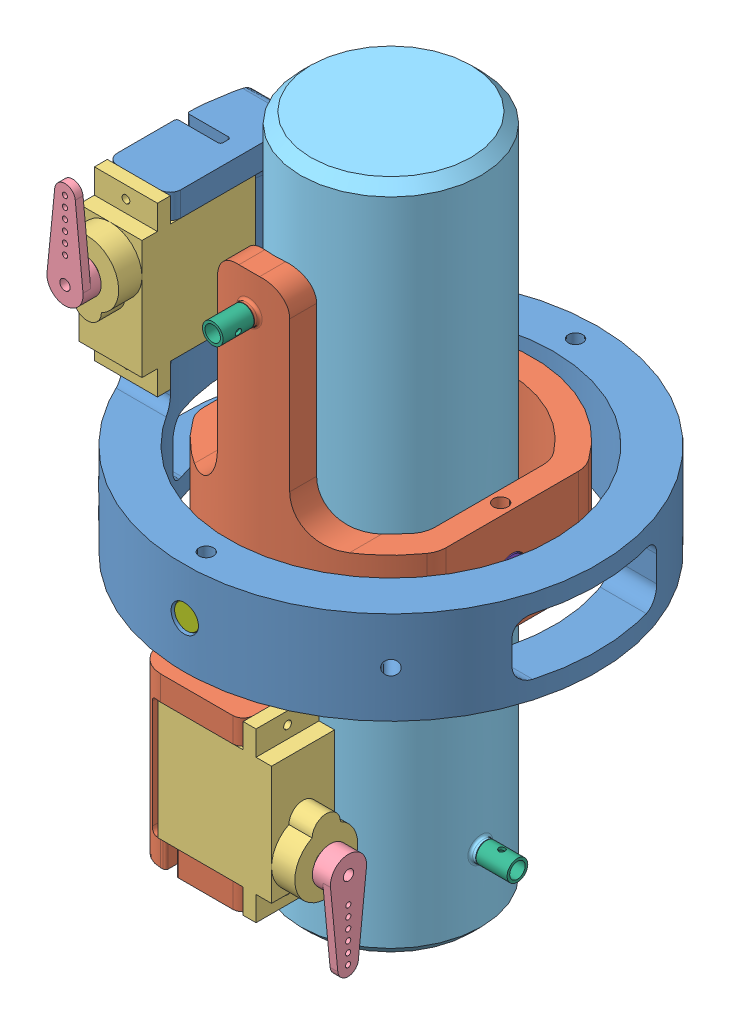
SolidWorks assembly Assemblage TVC, configuration Défaut. Lengths in mm.
Overall size (80 130 80).
13 component instances, 8 part files, 27 mates.
Components (placement in the parent):
- Cardan roulis-1: Cardan roulis [Défaut] at origin size (80 53.5 80)
- Cardan tangage-1: Cardan tangage [Défaut] at origin size (47 100.5 63.11)
- SG90-1: SG90 [Défaut] at (-33.7993 28.25 9.5) size (12.2 32.5 29.3)
- Biellette-1: Biellette [Défaut] at (-33.7993 33.65 29.3) x (-1 0 0) z (0 0 -1) size (7 20.5 3.5)
- Support moteur-1: Support moteur [Défaut] at origin size (36 130 35)
- SG90-2: SG90 [Défaut] at (1.5 -32.25 29.5139) x (0 0 1) z (1 0 0) size (12.2 32.5 29.3)
- Biellette-2: Biellette [Défaut] at (21.3 -37.65 29.5139) x (0 -0.004896 -0.999988) z (-1 0 0) size (7 20.5 3.5)
- Pivot-1: Pivot [Défaut] at (0 45 29) x (0.164225 0.986423 0) z (0 0 -1) size (4 4 11)
- Pivot-2: Pivot [Défaut] at (19 -50 0) x (0 0.007842 0.999969) z (-1 0 0) size (4 4 11)
- Axe roulis-1: Axe roulis [Défaut] at (0 0 32) size (5 5 15)
- Axe tangage-1: Axe tangage [Défaut] at (18.5 0 0) x (0 0.148183 0.98896) z (1 0 0) size (5 5 10)
- Axe roulis-2: Axe roulis [Défaut] at (0 0 -32) size (5 5 15)
- Axe tangage-2: Axe tangage [Défaut] at (-18.5 0 0) x (0 0.148183 0.98896) z (1 0 0) size (5 5 10)
Mates (geometry in assembly coordinates):
- Coïncidente1: coincident aligned: plane of Cardan roulis-1 through (0 0 0) normal (0 0 1); plane of assembly through (0 0 0) normal (0 0 1)
- Coïncidente2: coincident aligned: plane of Cardan roulis-1 through (0 0 0) normal (0 1 0); plane of assembly through (0 0 0) normal (0 1 0)
- Coïncidente3: coincident aligned: plane of Cardan roulis-1 through (0 0 0) normal (1 0 0); plane of assembly through (0 0 0) normal (1 0 0)
- Coïncidente4: coincident aligned: plane of Cardan roulis-1 through (0 0 0) normal (0 0 1); plane of Cardan tangage-1 through (0 0 0) normal (0 0 1)
- Coaxiale1: concentric aligned: cylinder of Cardan roulis-1 through (0 0 -40.001) axis (0 0 1) radius 2.65; cylinder of Cardan tangage-1 through (0 0 24.5) axis (0 0 1) radius 2.5
- Coïncidente6: coincident anti-aligned: plane of SG90-1 through (-33.7993 33.65 27.8) normal (0 0 1); plane of Biellette-1 through (-33.7993 33.65 27.8) normal (0 0 -1)
- Coaxiale2: concentric aligned: cylinder of SG90-1 through (-33.7993 33.65 27.8) axis (0 0 -1) radius 2.45; cylinder of Biellette-1 through (-33.7993 33.65 27.8) axis (0 0 -1) radius 2.45
- Coïncidente8: coincident aligned: plane of Cardan tangage-1 through (0 0 0) normal (1 0 0); plane of Support moteur-1 through (0 0 0) normal (1 0 0)
- Coaxiale3: concentric aligned: cylinder of Cardan tangage-1 through (-23.501 0 0) axis (1 0 0) radius 2.65; cylinder of Support moteur-1 through (13.5 0 0) axis (1 0 0) radius 2.65
- Coïncidente9: coincident: plane of ? through (-37.081 44.5 15) normal (0 0 1); plane of SG90-1 through (-27.6993 39.75 15) normal (0 0 -1)
- Coïncidente15: coincident anti-aligned: plane of Cardan roulis-1 through (40.001 16.75 15) normal (0 1 0); plane of SG90-1 through (-27.6993 16.75 -1.5) normal (0 -1 0)
- Coïncidente17: coincident anti-aligned: line of Cardan roulis-1 through (-27.6993 15.75 15) axis (0 -1 0); line of SG90-1 through (-27.6993 12 15) axis (0 1 0)
- Parallèle4: parallel anti-aligned: unknown of Biellette-1; plane of assembly through (0 0 0) normal (1 0 0)
- Coïncidente20: coincident anti-aligned: plane of Cardan tangage-1 through (7 -43.75 23.4139) normal (0 1 0); plane of SG90-2 through (-9.5 -43.75 35.6139) normal (0 -1 0)
- Coïncidente22: coincident anti-aligned: plane of Cardan tangage-1 through (0 0 23.4139) normal (0 0 1); plane of SG90-2 through (1.5 -32.25 23.4139) normal (0 0 -1)
- Coïncidente24: coincident anti-aligned: plane of SG90-2 through (7 -20.75 35.6139) normal (-1 0 0); plane of Cardan tangage-1 through (7 -16 26.5942) normal (1 0 0)
- Coïncidente25: coincident anti-aligned: plane of SG90-2 through (19.8 -37.65 29.5139) normal (1 0 0); plane of Biellette-2 through (19.8 -37.65 29.5139) normal (-1 0 0)
- Coaxiale4: concentric aligned: cylinder of SG90-2 through (19.8 -37.65 29.5139) axis (-1 0 0) radius 2.45; cylinder of Biellette-2 through (19.8 -37.65 29.5139) axis (-1 0 0) radius 2.45
- Parallèle5: parallel aligned: plane of Cardan roulis-1 through (0 -9 0) normal (0 -1 0); plane of Support moteur-1
- Coaxiale5: concentric anti-aligned: cylinder of Cardan tangage-1 through (0 45 -27.5) axis (0 0 1) radius 1.05; cylinder of Pivot-1 through (0 45 23.5) axis (0 0 -1) radius 1
- Coïncidente26: coincident anti-aligned: plane of Cardan tangage-1 through (0 45 28.5) normal (0 0 1); plane of Pivot-1 through (0.9864 44.8358 28.5) normal (0 0 -1)
- Coaxiale6: concentric anti-aligned: cylinder of Support moteur-1 through (-17.501 -50 0) axis (1 0 0) radius 1.05; cylinder of Pivot-2 through (13.5 -50 0) axis (-1 0 0) radius 1
- Coïncidente27: coincident anti-aligned: plane of Support moteur-1 through (18.5 -50 0) normal (1 0 0); plane of Pivot-2 through (18.5 -49 -0.0078) normal (-1 0 0)
- Coaxiale7: concentric anti-aligned: cylinder of Cardan roulis-1 through (0 0 -40.001) axis (0 0 1) radius 2.65; cylinder of Axe roulis-1 through (0 0 39.5) axis (0 0 -1) radius 2.5
- Coïncidente28: coincident anti-aligned: plane of Cardan tangage-1 through (0 0 24.5) normal (0 0 1); plane of Axe roulis-1 through (0 0 24.5) normal (0 0 -1)
- Coaxiale9: concentric anti-aligned: cylinder of Cardan tangage-1 through (-23.501 0 0) axis (1 0 0) radius 2.65; cylinder of Axe tangage-1 through (23.5 0 0) axis (-1 0 0) radius 2.5
- Coïncidente29: coincident anti-aligned: plane of Support moteur-1 through (13.5 0 0) normal (1 0 0); plane of Axe tangage-1 through (13.5 0 0) normal (-1 0 0)
